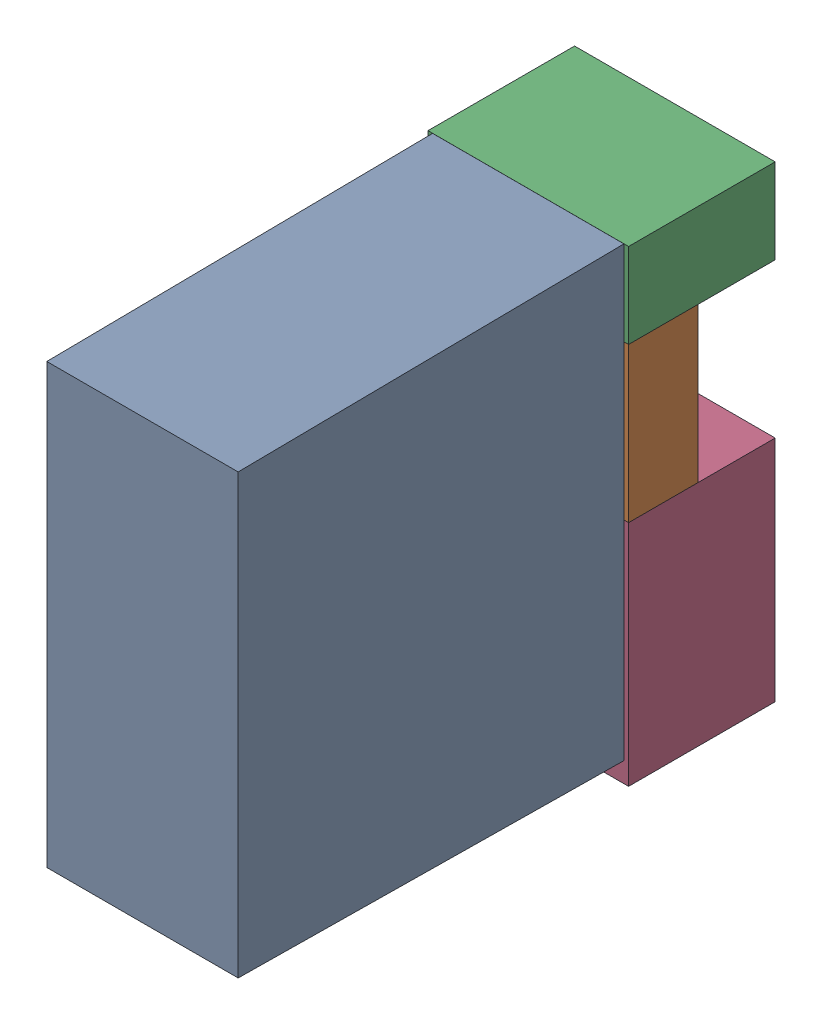
SolidWorks assembly K6, configuration Default. Lengths in mm.
Overall size (13 30.3 34.5).
7 component instances, 4 part files, 0 mates.
Components (placement in the parent):
- relais_40_61_8_006_0000-1: relais_40_61_8_006_0000 [Default] at (83.185 15.7216 9.5) x (0 1 0) z (1 0 0) size (29 30 12.4)
- 1151725064-1: 1151725064 [Default] at (83.185 34.225 5) size (13 10 4.5)
  - Extruded_3-1: Extruded_3 [Default] at origin size (13 10 4.5)
- 1151724928-1: 1151724928 [Default] at (83.185 41.975 0) size (13 5.5 9.5)
  - Extruded_2-1: Extruded_2 [Default] at origin size (13 5.5 9.5)
- 1151724792-1: 1151724792 [Default] at (83.185 21.825 0) size (13 14.8 9.5)
  - Extruded_4-1: Extruded_4 [Default] at origin size (13 14.8 9.5)
